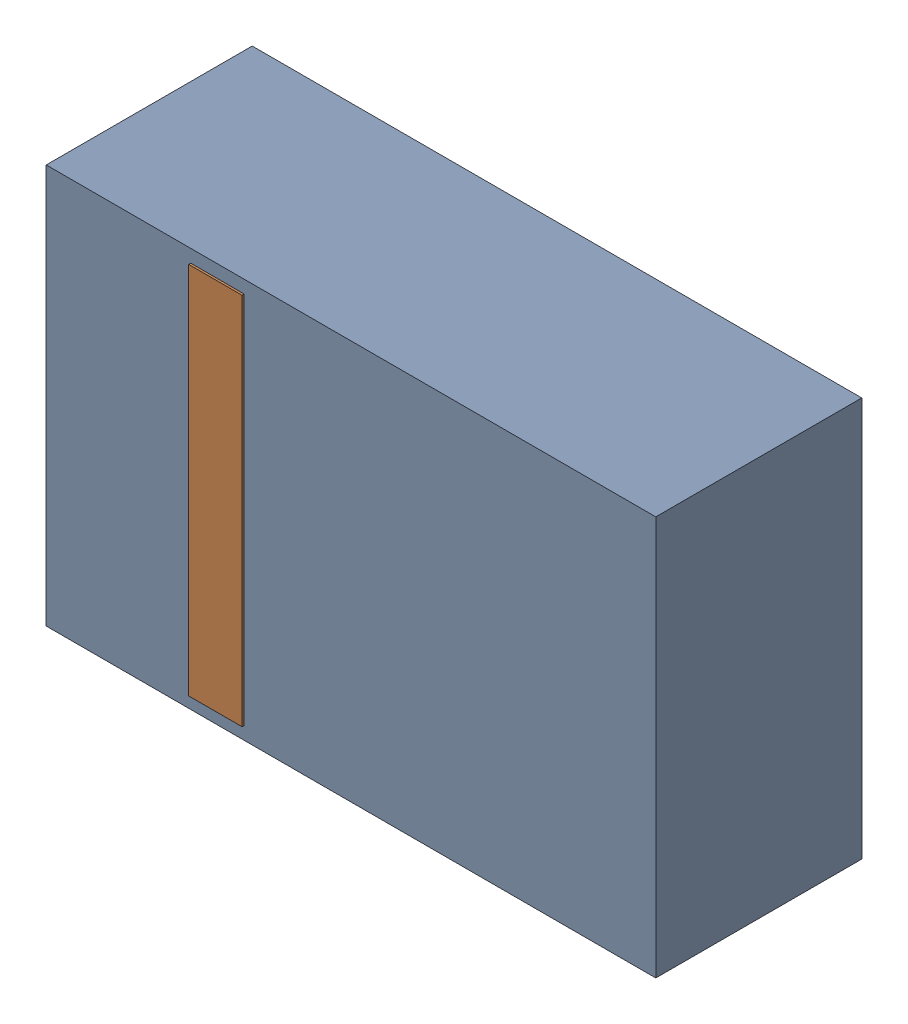
SolidWorks assembly D43, configuration Default. Lengths in mm.
Overall size (2.9 1.9 0.99).
4 component instances, 2 part files, 0 mates.
Components (placement in the parent):
- 905269392-1: 905269392 [Default] at (181.102 71.882 0) size (2.9 1.9 0.98)
  - Extruded_5-1: Extruded_5 [Default] at origin size (2.9 1.9 0.98)
- 905269800-1: 905269800 [Default] at (180.467 71.882 0.95) size (0.25 1.78 0.04)
  - Extruded_6-1: Extruded_6 [Default] at origin size (0.25 1.78 0.04)
